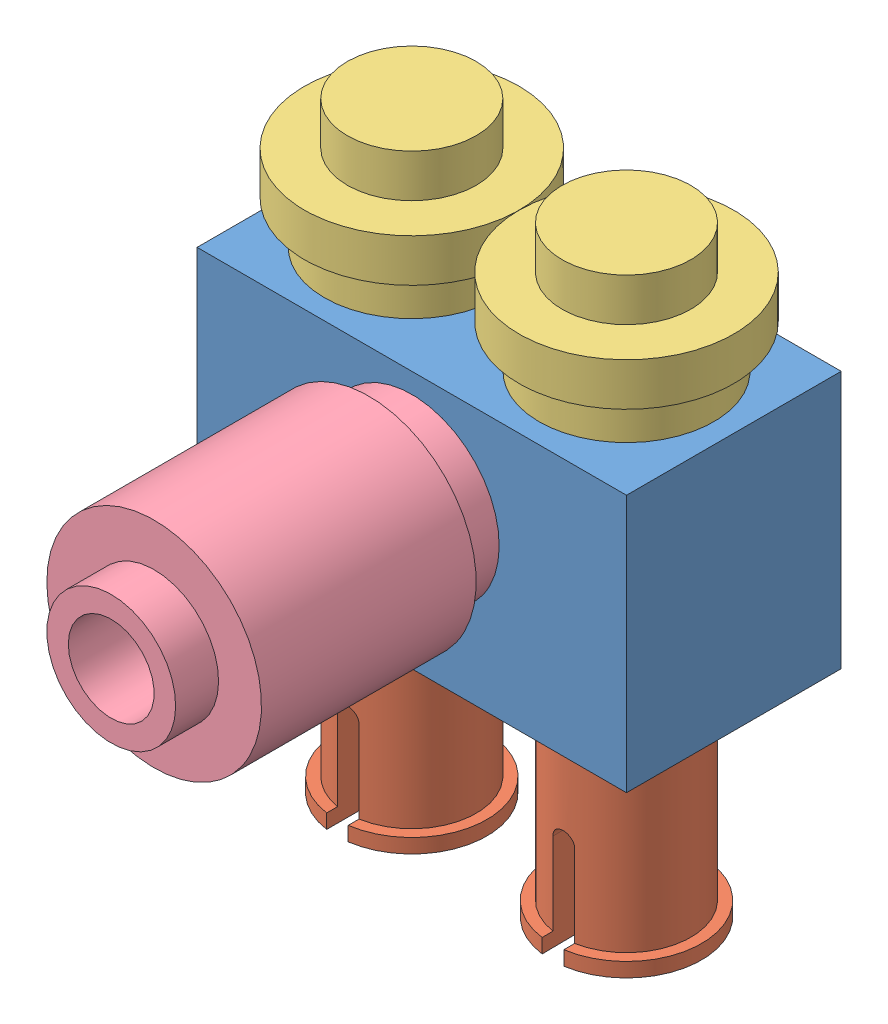
SolidWorks assembly Assem2, configuration Default. Lengths in mm.
Overall size (10.6 14 12.6).
7 component instances, 4 part files, 14 mates.
Components (placement in the parent):
- brick with hole 2x1 hole-1: brick with hole 2x1 hole [Default] at (-3.9941 2.7555 10.9103) size (10 7 5)
- connector peg w knob-1: connector peg w knob [Default] at (1.0059 6.2555 5.9103) x (0.999817 0.019121 0) z (0.019121 -0.999817 0) size (4 6 4)
- connector peg w knob-2: connector peg w knob [Default] at (3.5059 -2.2445 8.4103) x (-0.999926 0 0.012151) z (-0.012151 0 -0.999926) size (4 6 4)
- connector peg w knob-3: connector peg w knob [Default] at (-1.4941 -2.2445 8.4103) size (4 6 4)
- plate round 1x1-1: plate round 1x1 [Default] at (3.5059 9.7555 8.4103) x (0.959848 0 0.280522) z (-0.280522 0 0.959848) size (5 3 5)
- plate round 1x1-2: plate round 1x1 [Default] at (-1.4941 9.7555 8.4103) size (5 3 5)
- brick round 1x1-1: brick round 1x1 [Default] at (1.0059 6.2555 10.9103) x (0.521928 0.852989 0) z (0.852989 -0.521928 0) size (5 7 5)
Mates (geometry in assembly coordinates):
- Concentric1: concentric aligned: circle of brick with hole 2x1 hole-1; circle of connector peg w knob-1
- Coincident1: coincident aligned: plane of brick with hole 2x1 hole-1 through (-3.9941 8.7555 5.9103) normal (0 0 -1); plane of connector peg w knob-1 through (1.0059 6.2555 5.9103) normal (0 0 -1)
- Tangent1: tangent anti-aligned: plane of brick with hole 2x1 hole-1 through (5.0059 8.7555 6.9103) normal (-1 0 0); cylinder of connector peg w knob-2 through (3.5059 3.7555 8.4103) axis (0 -1 0) radius 1.5
- Tangent3: tangent anti-aligned: plane of brick with hole 2x1 hole-1 through (-2.9941 8.7555 6.9103) normal (0 0 1); cylinder of connector peg w knob-2 through (3.5059 3.7555 8.4103) axis (0 -1 0) radius 1.5
- Coincident2: coincident anti-aligned: plane of brick with hole 2x1 hole-1 through (-3.9941 2.7555 10.9103) normal (0 -1 0); plane of connector peg w knob-2 through (3.5059 2.7555 8.4103) normal (0 1 0)
- Coincident3: coincident anti-aligned: plane of brick with hole 2x1 hole-1 through (-3.9941 2.7555 10.9103) normal (0 -1 0); plane of connector peg w knob-3 through (-1.4941 2.7555 8.4103) normal (0 1 0)
- Tangent5: tangent anti-aligned: plane of brick with hole 2x1 hole-1 through (-2.9941 8.7555 9.9103) normal (0 0 -1); cylinder of connector peg w knob-3 through (-1.4941 3.7555 8.4103) axis (0 -1 0) radius 1.5
- Tangent6: tangent anti-aligned: plane of brick with hole 2x1 hole-1 through (-2.9941 8.7555 6.9103) normal (1 0 0); cylinder of connector peg w knob-3 through (-1.4941 3.7555 8.4103) axis (0 -1 0) radius 1.5
- Concentric2: concentric anti-aligned: circle of brick with hole 2x1 hole-1; circle of plate round 1x1-1
- Coincident5: coincident anti-aligned: plane of brick with hole 2x1 hole-1 through (-3.9941 8.7555 10.9103) normal (0 1 0); plane of plate round 1x1-1 through (3.5059 8.7555 8.4103) normal (0 -1 0)
- Coincident6: coincident anti-aligned: plane of brick with hole 2x1 hole-1 through (-3.9941 8.7555 10.9103) normal (0 1 0); plane of plate round 1x1-2 through (-1.4941 8.7555 8.4103) normal (0 -1 0)
- Concentric3: concentric aligned: circle of brick with hole 2x1 hole-1; circle of plate round 1x1-2
- Concentric4: concentric aligned: circle of connector peg w knob-1; circle of brick round 1x1-1
- Coincident9: coincident anti-aligned: plane of connector peg w knob-1 through (1.0059 6.2555 10.9103) normal (0 0 1); plane of brick round 1x1-1 through (1.0059 6.2555 10.9103) normal (0 0 -1)
